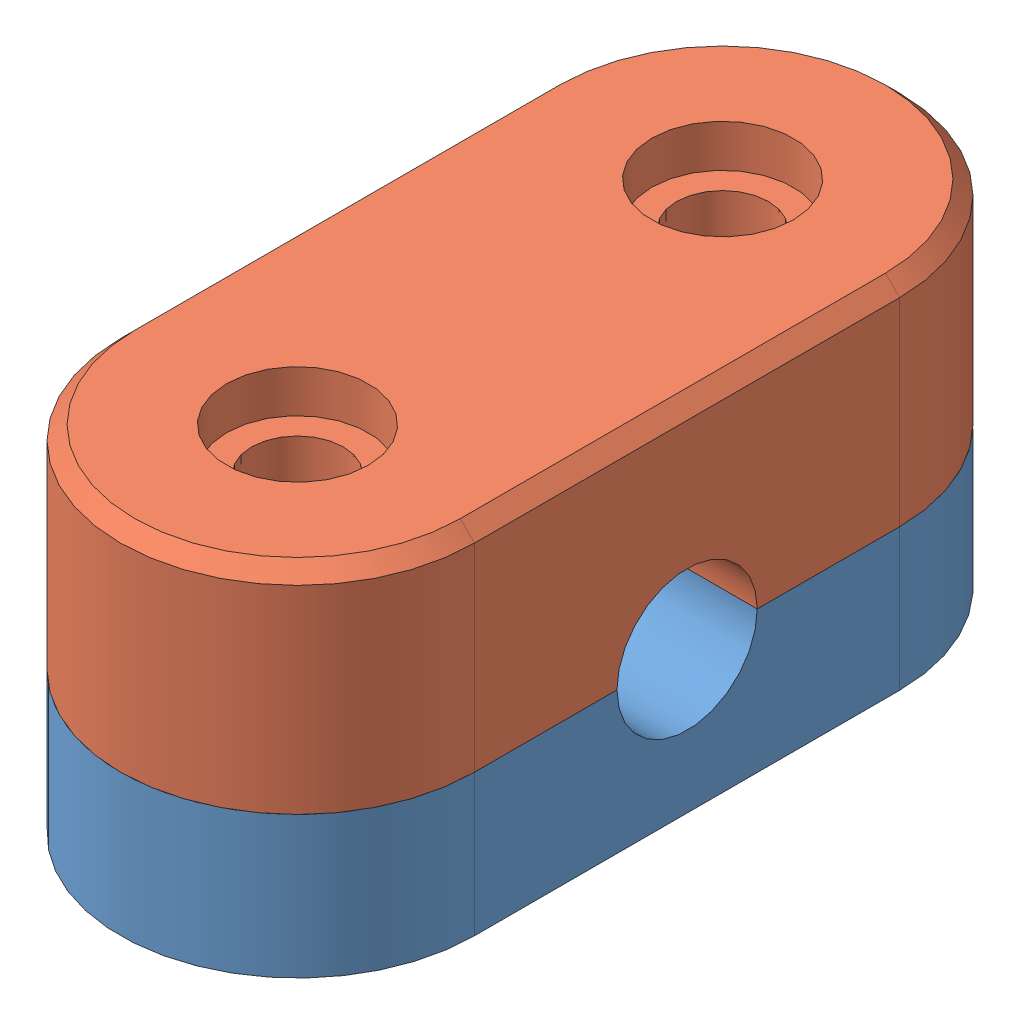
SolidWorks assembly axle-mount, configuration Default. Lengths in mm.
Overall size (25 25 55).
2 component instances, 2 part files, 4 mates.
Components (placement in the parent):
- axle-mount-bottom-1: axle-mount-bottom [Default] at origin size (25 10 55)
- axle-mount-top-1: axle-mount-top [Default] at (0 10 0) x (1 0 0) z (0 1 0) size (25 55 15)
Mates (geometry in assembly coordinates):
- InPlace1: in place: plane of axle-mount-bottom-1 through (0 10 0) normal (0 1 0); plane of axle-mount-top-1 through (0 10 0) normal (0 1 0); moOrthogonalPlaneRef_w of axle-mount-bottom-1 through (0 10 0) normal (0 1 0); plane of axle-mount-top-1 through (0 10 0) normal (0 0 -1); plane of axle-mount-bottom-1 through (0 10 0) normal (0 1 0); plane of axle-mount-top-1 through (0 10 0) normal (1 0 0); plane of axle-mount-bottom-1 through (0 10 0) normal (0 1 0); unknown of axle-mount-top-1
- Coincident1: coincident aligned: plane of ?; plane of ?
- Coincident2: coincident aligned: moOrthogonalPlaneRef_w of axle-mount-bottom-1 through (0 10 0) normal (0 0 -1); plane of Part6^axle-mount-1 through (0 10 0) normal (0 0 -1)
- Coincident3: coincident anti-aligned: moOrthogonalPlaneRef_w of axle-mount-bottom-1 through (0 10 0) normal (-1 0 0); plane of Part6^axle-mount-1 through (0 10 0) normal (1 0 0)
